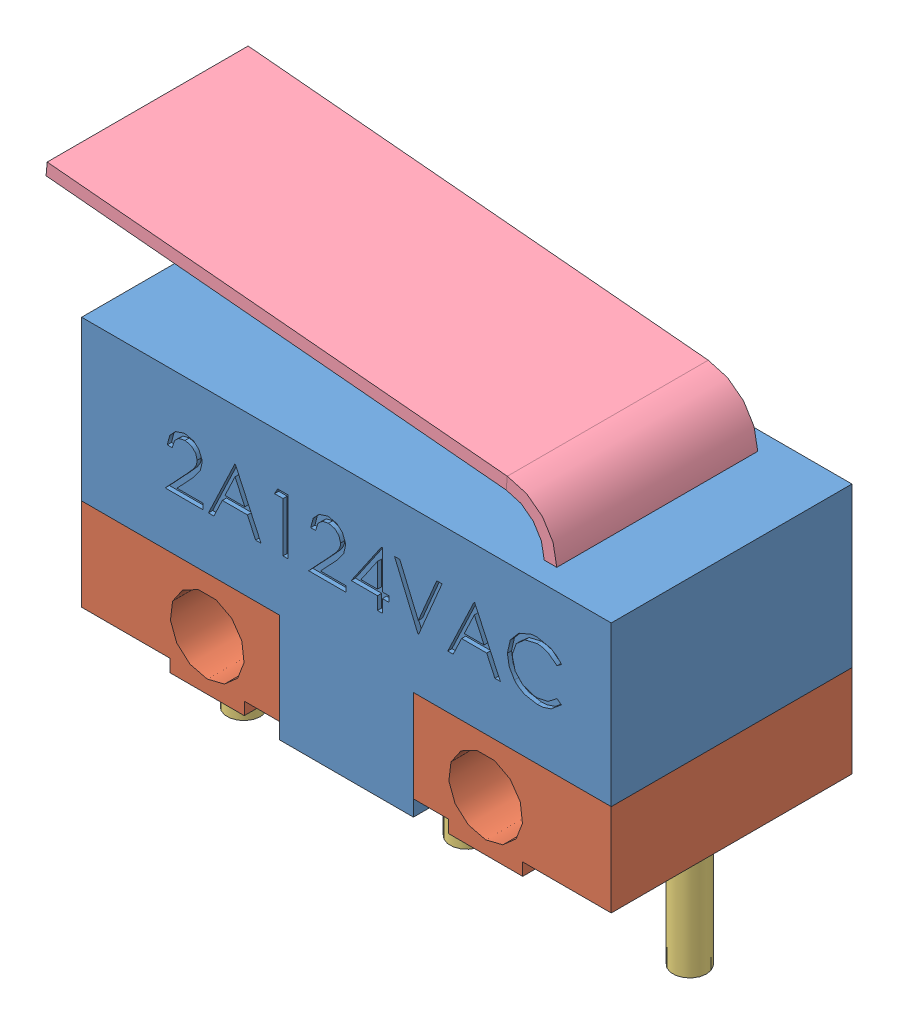
SolidWorks assembly User Library-switch-2, configuration Default. Lengths in mm.
Overall size (14 11.3 5.75).
5 component instances, 5 part files, 16 mates.
Components (placement in the parent):
- User Library-switch-2_switch_ust-1: User Library-switch-2_switch_ust [Default] at origin size (12.65 6.38 5.75)
- User Library-switch-2_switch_altSLDPRT-1: User Library-switch-2_switch_altSLDPRT [Default] at (0 -1.9 0) x (1 0 0) z (0 -1 0) size (12.65 5.75 2.5)
- User Library-switch-2_pin-1: User Library-switch-2_pin [Default] at (0 -4.1 0) x (1 0 0) z (0 -1 0) size (11.45 0.8 3)
- User Library-switch-2_switch_1-1: User Library-switch-2_switch_1 [Default] at (0 0 5.75) size (12.2 2.3 4.8)
- User Library-switch-2_buton-1: User Library-switch-2_buton [Default] at (0 1.9 0) x (-1 0 0) z (0 1 0) size (2 2 1.5)
Mates (geometry in assembly coordinates):
- InPlace1: in place: plane of User Library-switch-2_switch_ust-1 through (-6.325 -1.9 5.75) normal (0 -1 0); plane of User Library-switch-2_switch_altSLDPRT-1; moOrthogonalPlaneRef_w of User Library-switch-2_switch_ust-1; plane of User Library-switch-2_switch_altSLDPRT-1; moOrthogonalPlaneRef_w of User Library-switch-2_switch_ust-1; plane of User Library-switch-2_switch_altSLDPRT-1
- Coincident1: coincident aligned: plane of User Library-switch-2_switch_ust-1; plane of User Library-switch-2_switch_altSLDPRT-1
- Coincident2: coincident aligned: moOrthogonalPlaneRef_w of User Library-switch-2_switch_ust-1 through (0 -1.9 0) axis (0 0 1); plane of User Library-switch-2_switch_altSLDPRT-1 through (0 -1.9 0) normal (0 0 1)
- Coincident3: coincident anti-aligned: moOrthogonalPlaneRef_w of User Library-switch-2_switch_ust-1 through (-1000 0 -1.9) axis (0 -1 0); plane of User Library-switch-2_switch_altSLDPRT-1
- InPlace2: in place: plane of User Library-switch-2_switch_altSLDPRT-1 through (-6.325 -4.1 -0.001) normal (0 -1 0); plane of User Library-switch-2_pin-1; moOrthogonalPlaneRef_w of User Library-switch-2_switch_altSLDPRT-1; plane of User Library-switch-2_pin-1; moOrthogonalPlaneRef_w of User Library-switch-2_switch_altSLDPRT-1; plane of User Library-switch-2_pin-1
- Coincident1: coincident aligned: plane of User Library-switch-2_switch_altSLDPRT-1; plane of User Library-switch-2_pin-1
- Coincident2: coincident aligned: moOrthogonalPlaneRef_w of User Library-switch-2_switch_altSLDPRT-1 through (0 -4.1 0) axis (0 0 1); plane of User Library-switch-2_pin-1 through (0 -4.1 0) normal (0 0 1)
- Coincident3: coincident anti-aligned: moOrthogonalPlaneRef_w of User Library-switch-2_switch_altSLDPRT-1 through (-1000 0 -4.1) axis (0 -1 0); plane of User Library-switch-2_pin-1
- InPlace3: in place: plane of User Library-switch-2_switch_ust-1 through (-6.325 -1.9 5.75) normal (0 0 1); plane of User Library-switch-2_switch_1-1; moOrthogonalPlaneRef_w of User Library-switch-2_switch_ust-1; plane of User Library-switch-2_switch_1-1; moOrthogonalPlaneRef_w of User Library-switch-2_switch_ust-1; plane of User Library-switch-2_switch_1-1
- Coincident4: coincident aligned: plane of User Library-switch-2_switch_ust-1; plane of User Library-switch-2_switch_1-1
- Coincident5: coincident aligned: moOrthogonalPlaneRef_w of User Library-switch-2_switch_ust-1 through (0 0 5.75) axis (0 1 0); plane of User Library-switch-2_switch_1-1 through (0 0 5.75) normal (0 1 0)
- Coincident6: coincident anti-aligned: moOrthogonalPlaneRef_w of User Library-switch-2_switch_ust-1 through (0 0 5.75) axis (-1 0 0); plane of User Library-switch-2_switch_1-1 through (0 0 5.75) normal (1 0 0)
- InPlace4: in place: plane of User Library-switch-2_switch_ust-1 through (-6.325 1.9 5.75) normal (0 1 0); plane of User Library-switch-2_buton-1; moOrthogonalPlaneRef_w of User Library-switch-2_switch_ust-1; plane of User Library-switch-2_buton-1; moOrthogonalPlaneRef_w of User Library-switch-2_switch_ust-1; plane of User Library-switch-2_buton-1
- Coincident7: coincident aligned: plane of User Library-switch-2_switch_ust-1; plane of User Library-switch-2_buton-1
- Coincident8: coincident aligned: moOrthogonalPlaneRef_w of User Library-switch-2_switch_ust-1 through (0 1.9 0) axis (0 0 1); plane of User Library-switch-2_buton-1
- Coincident9: coincident anti-aligned: moOrthogonalPlaneRef_w of User Library-switch-2_switch_ust-1 through (-1000 0 1.9) axis (0 1 0); plane of User Library-switch-2_buton-1
